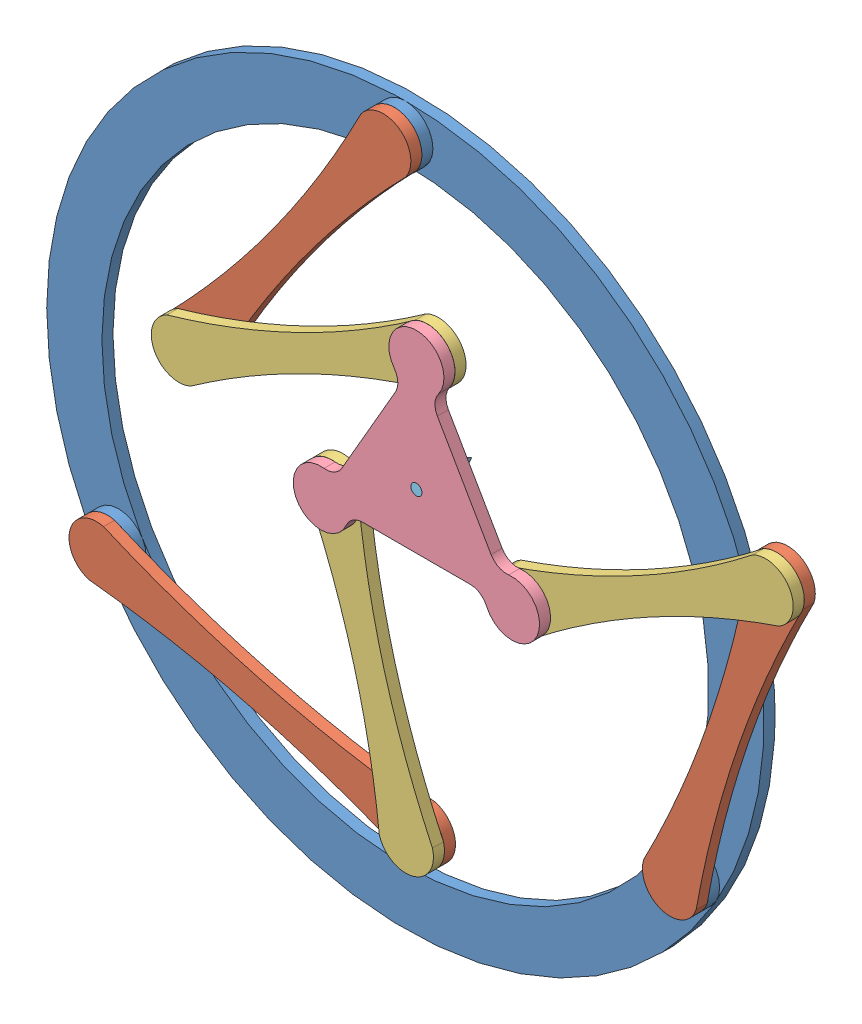
SolidWorks assembly 3RRR - Elbow Down, configuration Default. Lengths in mm.
Overall size (715.35 659.89 50).
9 component instances, 5 part files, 21 mates.
Components (placement in the parent):
- Base-1: Base [Default] at origin size (650 650 20)
- Proximal Link-1: Proximal Link [Default] at (-114.6799 -187.9204 20) x (0.967518 -0.252802 0) z (0 0 1) size (350 50 20)
- Proximal Link-2: Proximal Link [Default] at (308.1348 -7.9983 20) x (0.322181 0.946678 0) z (0 0 1) size (350 50 20)
- Proximal Link-3: Proximal Link [Default] at (-87.612 178.2456 20) x (-0.58408 -0.811696 0) z (0 0 1) size (350 50 20)
- Distal Link-1: Distal Link [Default] at (-3.0774 -105.4204 30) x (-0.268201 0.963363 0) z (0 0 1) size (300 50 20)
- Distal Link-2: Distal Link [Default] at (246.5323 74.5017 30) x (-0.879438 -0.476014 0) z (0 0 1) size (300 50 20)
- Distal Link-3: Distal Link [Default] at (-62.612 110.7455 30) x (0.900896 0.434035 0) z (0 0 1) size (300 50 20)
- Platform-1: Platform [Default] at (50 65 50) x (-0.5 -0.866026 0) z (0 0 1) size (223.21 200 20)
- Pen-1: Pen [Default] at (50 65 50) x (-0.808883 0.58797 0) z (0 0 -1) size (10 10 50)
Mates (geometry in assembly coordinates):
- Coincident5: coordinate: unknown of Base-1
- Concentric1: concentric anti-aligned: cylinder of Base-1 through (-259.8076 -150 20) axis (0 0 -1) radius 16.25; cylinder of Proximal Link-1 through (-259.8076 -150 10) axis (0 0 1) radius 16.25
- Coincident6: coincident anti-aligned: plane of Base-1 through (0 0 10) normal (0 0 1); plane of Proximal Link-1 through (-259.8076 -150 10) normal (0 0 -1)
- Concentric2: concentric anti-aligned: cylinder of Base-1 through (259.8076 -150 20) axis (0 0 -1) radius 16.25; cylinder of Proximal Link-2 through (259.8076 -150 10) axis (0 0 1) radius 16.25
- Coincident7: coincident anti-aligned: plane of Base-1 through (0 0 10) normal (0 0 1); plane of Proximal Link-2 through (259.8076 -150 10) normal (0 0 -1)
- Concentric3: concentric anti-aligned: cylinder of Base-1 through (0 300 20) axis (0 0 -1) radius 16.25; cylinder of Proximal Link-3 through (0 300 10) axis (0 0 1) radius 16.25
- Coincident8: coincident anti-aligned: plane of Base-1 through (0 0 10) normal (0 0 1); plane of Proximal Link-3 through (0 300 10) normal (0 0 -1)
- Concentric4: concentric aligned: cylinder of Proximal Link-1 through (30.4478 -225.8407 20) axis (0 0 1) radius 16.25; cylinder of Distal Link-1 through (30.4478 -225.8407 20) axis (0 0 1) radius 16.25
- Coincident9: coincident anti-aligned: plane of Proximal Link-1 through (86.0151 283.4991 30) normal (0 0 1); plane of Distal Link-1 through (-388.0902 -147.7313 30) normal (0 0 -1)
- Concentric5: concentric aligned: cylinder of Proximal Link-2 through (356.462 134.0034 20) axis (0 0 1) radius 16.25; cylinder of Distal Link-2 through (356.462 134.0034 20) axis (0 0 1) radius 16.25
- Coincident10: coincident anti-aligned: plane of Proximal Link-2 through (-147.5187 226.2979 30) normal (0 0 1); plane of Distal Link-2 through (373.526 -291.4187 30) normal (0 0 -1)
- Concentric6: concentric aligned: cylinder of Proximal Link-3 through (-175.2239 56.4911 20) axis (0 0 1) radius 16.25; cylinder of Distal Link-3 through (-175.2239 56.4911 20) axis (0 0 1) radius 16.25
- Coincident11: coincident anti-aligned: plane of Proximal Link-3 through (279.9846 -178.6684 30) normal (0 0 1); plane of Distal Link-3 through (-172.2181 482.2447 30) normal (0 0 -1)
- Concentric8: concentric aligned: cylinder of Distal Link-1 through (-36.6025 15 30) axis (0 0 1) radius 16.25; cylinder of Platform-1 through (-36.6025 15 30) axis (0 0 1) radius 16.25
- Coincident12: coincident anti-aligned: plane of Distal Link-1 through (-388.0902 -147.7313 40) normal (0 0 1); plane of Platform-1 through (98.6882 -1.25 40) normal (0 0 -1)
- Concentric9: concentric aligned: cylinder of Distal Link-2 through (136.6025 15 30) axis (0 0 1) radius 16.25; cylinder of Platform-1 through (136.6025 15 30) axis (0 0 1) radius 16.25
- Concentric10: concentric aligned: cylinder of Distal Link-3 through (50 164.9999 30) axis (0 0 1) radius 16.25; cylinder of Platform-1 through (50 164.9999 30) axis (0 0 1) radius 16.25
- Distance2: distance = 15 mm anti-aligned: plane of Platform-1 through (98.6882 15 40) normal (0 -1 0)
- Distance1: distance = 96.0469 mm: point of assembly; point of assembly; point of Platform-1
- Coincident13: coincident aligned: plane of Platform-1 through (98.6882 -1.25 50) normal (0 0 1); plane of Pen-1 through (50 65 50) normal (0 0 1)
- Concentric11: concentric aligned: cylinder of Platform-1 through (50 65 40) axis (0 0 1) radius 5; cylinder of Pen-1 through (50 65 10) axis (0 0 1) radius 5
